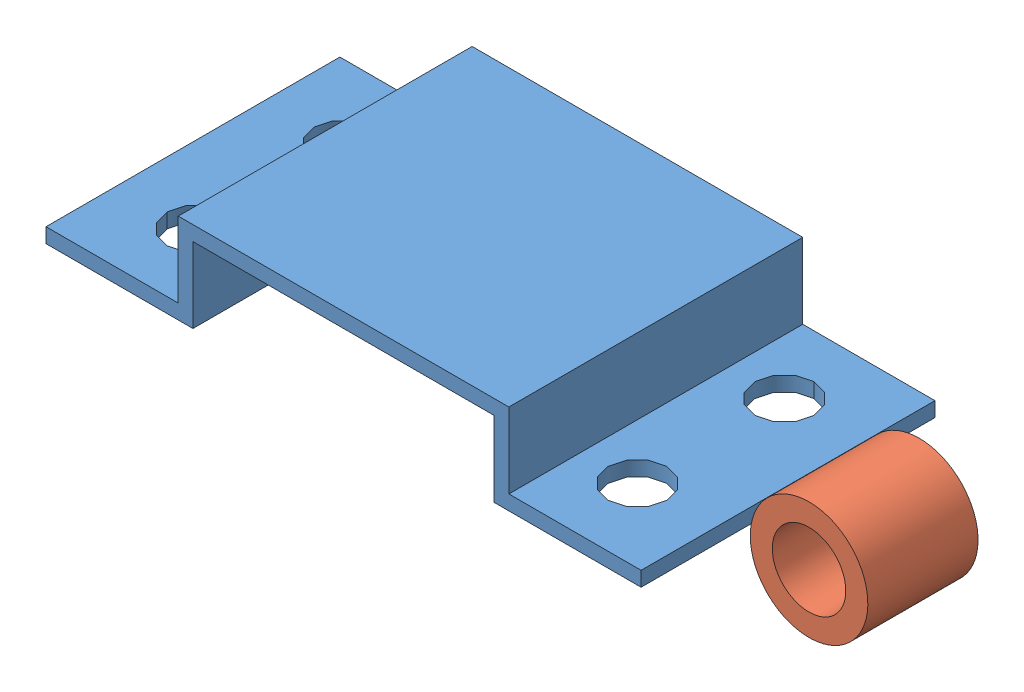
SolidWorks assembly СкобаМ2, configuration По умолчанию. Lengths in mm.
Overall size (99.31 57.49 47).
2 component instances, 2 part files, 3 mates.
Components (placement in the parent):
- Скоба-1: Скоба [По умолчанию] at (68.8429 -12.25 0) x (0 0 -1) z (1 0 0) size (47 57.49 81)
- Втулка-1: Втулка [По умолчанию] at (117.2011 -13.75 -15) x (-0.923728 -0.383049 0) z (0.383049 -0.923728 0) size (16 15 16)
Mates (geometry in assembly coordinates):
- Расстояние2: distance = 15 mm aligned: plane of Скоба-1 through (68.8429 -12.25 0) normal (0 0 1); plane of Втулка-1 through (117.2011 -13.75 -15) normal (0 0 1)
- Совпадение5: coincident: line of Скоба-1 through (109.3429 -12.25 -47) axis (0 0 1); cylinder of Втулка-1 through (117.2011 -13.75 -30) axis (0 0 1) radius 8
- Расстояние1: distance = 1.5 mm: cylinder of Втулка-1 through (117.2011 -13.75 -30) axis (0 0 1) radius 8; plane of Скоба-1 through (109.3429 -12.25 -47) normal (0 -1 0)
